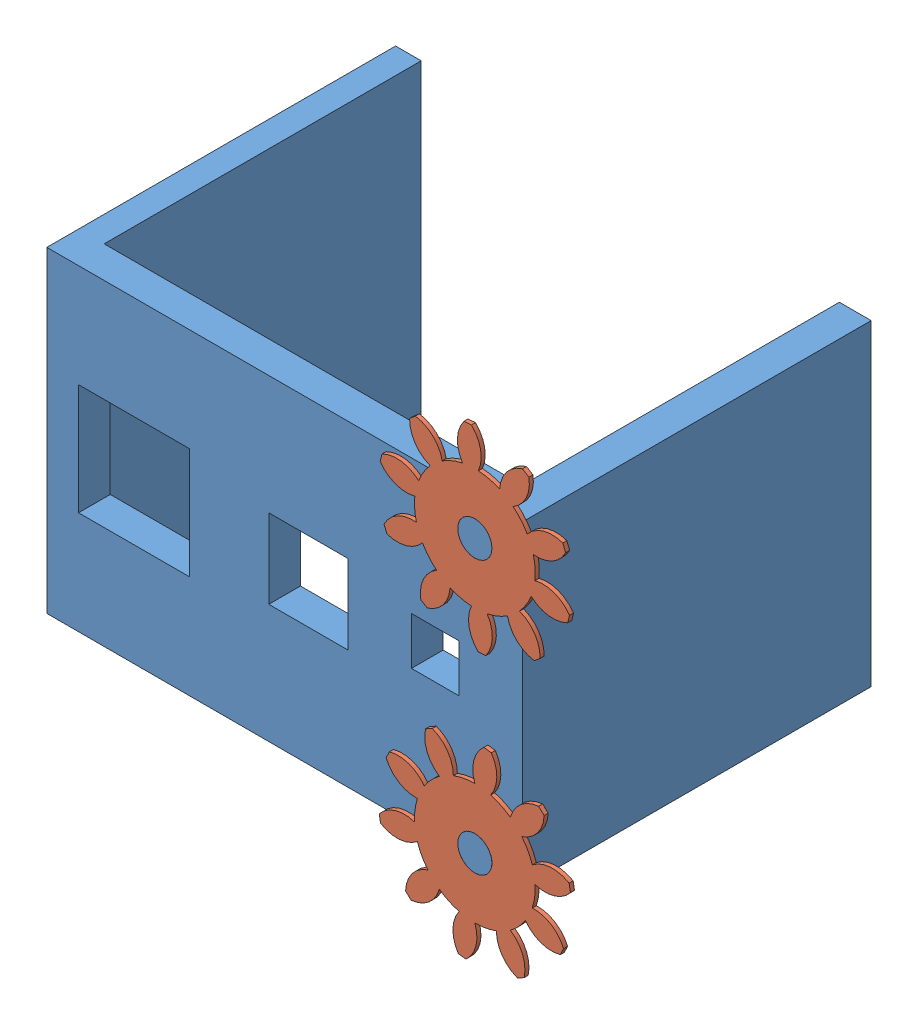
SolidWorks assembly Assem2, configuration Default. Lengths in mm.
Overall size (1809.87 1614.41 1150).
3 component instances, 2 part files, 4 mates.
Components (placement in the parent):
- devider-1: devider [Default] at (308.0736 947.2549 1172.5284) size (1500 1000 1150)
- spur gear_ai-1: spur gear_ai [Inch - Spur gear 0.5DP 10T 14.5PA .5FW ---S10N3.0H2.0L4.25N] at (1228.9345 1272.6192 1322.5284) x (0 0 -1) z (0.526422 0.850224 0) size (12.7 586.72 609.6)
- spur gear_ai-2: spur gear_ai [Inch - Spur gear 0.5DP 10T 14.5PA .5FW ---S10N3.0H2.0L4.25N] at (1228.9345 412.6192 1322.5284) x (0 0 -1) z (-0.131916 -0.991261 0) size (12.7 586.72 609.6)
Mates (geometry in assembly coordinates):
- Concentric1: concentric anti-aligned: circle of devider-1; circle of spur gear_ai-1
- Coincident1: coincident aligned: plane of devider-1 through (1228.9345 1272.6192 1322.5284) normal (0 0 1); plane of spur gear_ai-1 through (1228.9345 1272.6192 1322.5284) normal (0 0 1)
- Concentric2: concentric anti-aligned: circle of devider-1; circle of spur gear_ai-2
- Coincident2: coincident aligned: plane of devider-1 through (1228.9345 412.6192 1322.5284) normal (0 0 1); plane of spur gear_ai-2 through (1228.9345 412.6192 1322.5284) normal (0 0 1)
